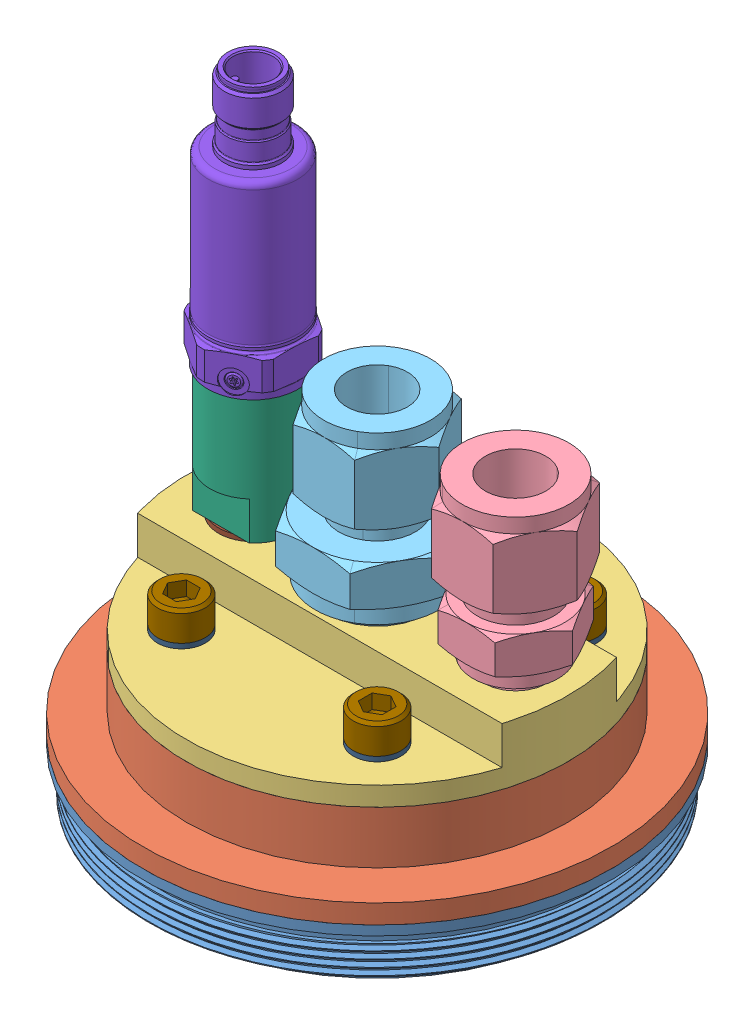
SolidWorks assembly Injector 98mm V02, configuration Standard. Lengths in mm.
Overall size (138.59 129.3 138.59).
19 component instances, 11 part files, 28 mates.
Components (placement in the parent):
- Faceplate 98mm-1: Faceplate 98mm [Standard] x (-0.707107 0 -0.707107) z (0.707107 0 -0.707107) size (98 14 98)
- Manifold 98mm-1: Manifold 98mm [Standard] at (0 14 0) size (98 15 98)
- Core 98mm-1: Core 98mm [Standard] at (0 -3 0) size (80 44 80)
- SS-810-1-4RS-SwagelokCompany-3D-10-18-2022.stp-1: SS-810-1-4RS-SwagelokCompany-3D-10-18-2022.stp [Standard] at (29 75.766 0) x (0 -1 0) z (-0.5 0 0.866025) size (44.7 22.35 25.81)
- SS-810-1-8RS-SwagelokCompany-3D-10-18-2022.stp-1: SS-810-1-8RS-SwagelokCompany-3D-10-18-2022.stp [Standard] at (0 76.528 0) x (0 -1 0) z (0.5 0 0.866025) size (47.5 26.99 31.16)
- Pressure sensor tube-1: Pressure sensor tube [Standard] at (-26 -2 0) x (0 0 -1) z (1 0 0) size (18 70 18)
- Diverter 98mm-1: Diverter 98mm [Standard] at (0 -7.2 0) x (0.998923 0 0.046395) z (-0.046395 0 0.998923) size (19 24.43 19)
- CAD_STP_500_0186-1: CAD_STP_500_0186 [Standard] at (-26 48.3 0) x (0 1 0) z (-0.050182 0 0.99874) size (73.8 19.02 21)
  - CAD_STP_500_0186.stp-1: CAD_STP_500_0186.stp [Standard] at origin size (73.8 19.02 21)
    - _PL54XX_P1.stp-1: _PL54XX_P1.stp [Standard] at origin size (73.8 19.02 21)
- CB6-25.stp-1: CB6-25.stp [Standard] at (-20.5061 34 20.5061) x (0 -1 0) z (0 0 1) size (31 10 10)
- CB6-25.stp-2: CB6-25.stp [Standard] at (-20.5061 34 -20.5061) x (0 -1 0) z (-1 0 0) size (31 10 10)
- CB6-25.stp-3: CB6-25.stp [Standard] at (20.5061 34 -20.5061) x (0 -1 0) z (0 0 -1) size (31 10 10)
- CB6-25.stp-4: CB6-25.stp [Standard] at (20.5061 34 20.5061) x (0 -1 0) z (1 0 0) size (31 10 10)
- M6 bolt seal-1: M6 bolt seal [Standard] at (-20.5061 34 20.5061) x (0.989025 0 -0.147746) z (0 -1 0) size (10 10 1)
- M6 bolt seal-2: M6 bolt seal [Standard] at (-20.5061 34 -20.5061) x (0.147746 0 0.989025) z (0 -1 0) size (10 10 1)
- M6 bolt seal-3: M6 bolt seal [Standard] at (20.5061 34 -20.5061) x (-0.989025 0 0.147746) z (0 -1 0) size (10 10 1)
- M6 bolt seal-4: M6 bolt seal [Standard] at (20.5061 34 20.5061) x (-0.147746 0 -0.989025) z (0 -1 0) size (10 10 1)
- Seal pressure sensor-1: Seal pressure sensor [Standard] at (-26 41 0) size (14.4 1 14.4)
Mates (geometry in assembly coordinates):
- Coincident3: coincident anti-aligned: plane of Faceplate 98mm-1 through (7.1418 0 7.1418) normal (0 -1 0)
- Concentric4: concentric aligned: cylinder of Manifold 98mm-1 through (0 14 0) axis (0 -1 0) radius 14; cylinder of Core 98mm-1 through (0 -3 0) axis (0 -1 0) radius 12
- Concentric5: concentric: cylinder of Faceplate 98mm-1 through (0 0 0) axis (0 -1 0) radius 10.1
- Coincident4: coincident anti-aligned: plane of Faceplate 98mm-1 through (34.6482 14 34.6482) normal (0 1 0); plane of Manifold 98mm-1 through (-45 14 0) normal (0 -1 0)
- Concentric7: concentric aligned: cylinder of Core 98mm-1 through (0 41 0) axis (0 1 0) radius 9.3155; cylinder of SS-810-1-8RS-SwagelokCompany-3D-10-18-2022.stp-1 through (0 34.0889 0) axis (0 1 0) radius 10.4775
- Distance2: distance = 2 mm anti-aligned: plane of SS-810-1-8RS-SwagelokCompany-3D-10-18-2022.stp-1 through (0 43 0) normal (0 -1 0); plane of Core 98mm-1 through (-40 41 0) normal (0 1 0)
- Concentric8: concentric aligned: cylinder of Core 98mm-1 through (29 41 0) axis (0 1 0) radius 5.7225; cylinder of SS-810-1-4RS-SwagelokCompany-3D-10-18-2022.stp-1 through (29 35.6563 0) axis (0 1 0) radius 6.5785
- Distance3: distance = 2 mm anti-aligned: plane of SS-810-1-4RS-SwagelokCompany-3D-10-18-2022.stp-1 through (29 43 0) normal (0 -1 0); plane of Core 98mm-1 through (-40 41 0) normal (0 1 0)
- Parallel1: parallel anti-aligned: plane of Manifold 98mm-1 through (0 21 3) normal (0 0 -1)
- Concentric9: concentric aligned: cylinder of Faceplate 98mm-1 through (0 0 0) axis (0 -1 0) radius 10.1; cylinder of Manifold 98mm-1 through (0 14 0) axis (0 -1 0) radius 14
- Coincident5: coincident anti-aligned: plane of Manifold 98mm-1 through (-36 29 0) normal (0 1 0); plane of Core 98mm-1 through (-14 29 0) normal (0 -1 0)
- Concentric10: concentric aligned: cylinder of Manifold 98mm-1 through (-20.5061 29 20.5061) axis (0 1 0) radius 3.5; cylinder of Core 98mm-1 through (-20.5061 41 20.5061) axis (0 1 0) radius 3.5
- Concentric11: concentric aligned: cylinder of Faceplate 98mm-1 through (-26 14 0) axis (0 1 0) radius 3.05; cylinder of Core 98mm-1 through (-26 41 0) axis (0 1 0) radius 3.4
- Concentric12: concentric anti-aligned: cylinder of Core 98mm-1 through (-26 41 0) axis (0 1 0) radius 3.4; cylinder of Pressure sensor tube-1 through (-26 -2 0) axis (0 -1 0) radius 9
- Distance4: distance = 1 mm anti-aligned: plane of Pressure sensor tube-1 through (-26 42 9) normal (0 -1 0); plane of Core 98mm-1 through (-40 41 0) normal (0 1 0)
- Concentric13: concentric anti-aligned: cylinder of Core 98mm-1 through (0 -3 0) axis (0 -1 0) radius 7.5; cylinder of Diverter 98mm-1 through (0 17 0) axis (0 1 0) radius 5
- Coincident7: coincident anti-aligned: plane of Core 98mm-1 through (0 5 0) normal (0 -1 0); plane of Diverter 98mm-1 through (-2.9968 5 -0.1392) normal (0 1 0)
- Concentric14: concentric anti-aligned: cylinder of Pressure sensor tube-1 through (-26 68 0) axis (0 1 0) radius 5.7225; cylinder of CAD_STP_500_0186-1/CAD_STP_500_0186.stp-1/_PL54XX_P1.stp-1 through (-26 68 0) axis (0 -1 0) radius 6.58
- Coincident8: coincident anti-aligned: plane of Pressure sensor tube-1 through (-26 68 0.75) normal (0 1 0); plane of CAD_STP_500_0186-1/CAD_STP_500_0186.stp-1/_PL54XX_P1.stp-1 through (-31.9924 68 -0.3011) normal (0 -1 0)
- Parallel2: parallel aligned: plane of Core 98mm-1 through (-114.5543 -207.0868 -12) normal (0 0 -1); plane of Pressure sensor tube-1 through (-34.0357 50 -6.75) normal (0 0 -1)
- Parallel3: parallel aligned: plane of Core 98mm-1 through (-114.5543 -207.0868 -12) normal (0 0 -1); plane of SS-810-1-8RS-SwagelokCompany-3D-10-18-2022.stp-1 through (7.7906 54.684 -13.4938) normal (0 0 -1)
- Parallel4: parallel aligned: plane of Core 98mm-1 through (-114.5543 -207.0868 -12) normal (0 0 -1); plane of SS-810-1-4RS-SwagelokCompany-3D-10-18-2022.stp-1 through (34.9575 53.922 -10.3187) normal (0 0 -1)
- Concentric15: concentric anti-aligned: cylinder of Core 98mm-1 through (-20.5061 41 20.5061) axis (0 1 0) radius 3.5; cylinder of CB6-25.stp-1 through (-20.5061 9 20.5061) axis (0 -1 0) radius 3
- Distance5: distance = 1 mm anti-aligned: plane of CB6-25.stp-1 through (-15.5061 34 20.5061) normal (0 -1 0); plane of Core 98mm-1 through (-14 33 0) normal (0 1 0)
- Concentric17: concentric anti-aligned: cylinder of CB6-25.stp-1 through (-20.5061 9 20.5061) axis (0 -1 0) radius 5; cylinder of M6 bolt seal-1 through (-20.5061 33 20.5061) axis (0 1 0) radius 5
- Coincident10: coincident anti-aligned: plane of CB6-25.stp-1 through (-15.5061 34 20.5061) normal (0 -1 0); plane of M6 bolt seal-1 through (-20.5061 34 20.5061) normal (0 1 0)
- Coincident11: coincident: plane of Core 98mm-1 through (-40 41 0) normal (0 1 0); plane of Seal pressure sensor-1 through (-30.2 41 0) normal (0 -1 0)
- Concentric18: concentric aligned: cylinder of Pressure sensor tube-1 through (-26 -2 0) axis (0 -1 0) radius 9; cylinder of Seal pressure sensor-1 through (-26 41 0) axis (0 -1 0) radius 7.2
